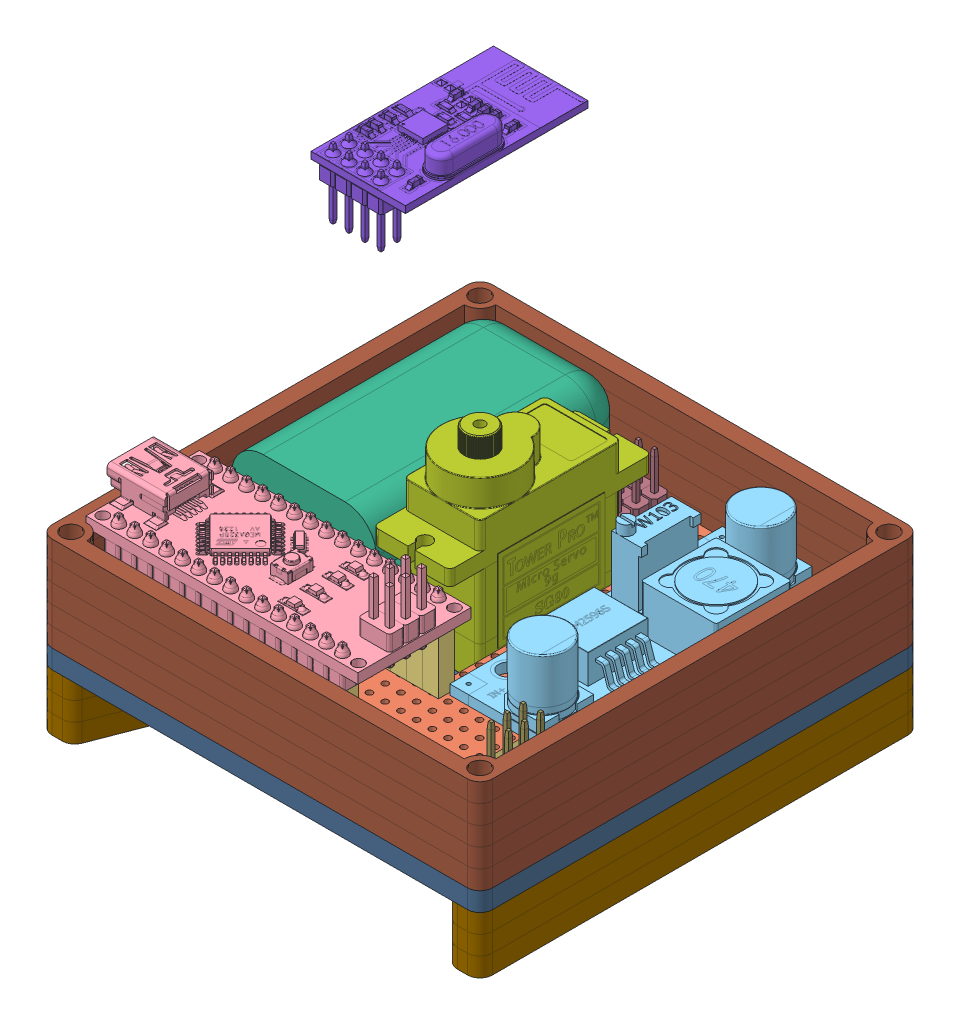
SolidWorks assembly base assembly modified, configuration Default. Lengths in mm.
Overall size (105.64 41.85 107.79).
27 component instances, 14 part files, 65 mates.
Components (placement in the parent):
- hex nut style 1_am-1: hex nut style 1_am [B18.2.4.1M - Hex nut, Style 1,  M3 x 0.5 --D-N] at (-15.0478 14.4 2.5048) x (1 0 0) z (0 1 0) size (5.5 6.35 2.4)
- hex nut style 1_am-2: hex nut style 1_am [B18.2.4.1M - Hex nut, Style 1,  M3 x 0.5 --D-N] at (-65.0478 12 2.5048) x (1 0 0) z (0 -1 0) size (5.5 6.35 2.4)
- hex nut style 1_am-3: hex nut style 1_am [B18.2.4.1M - Hex nut, Style 1,  M3 x 0.5 --D-N] at (-15.0478 14.4 52.5048) x (1 0 0) z (0 1 0) size (5.5 6.35 2.4)
- hex nut style 1_am-4: hex nut style 1_am [B18.2.4.1M - Hex nut, Style 1,  M3 x 0.5 --D-N] at (-65.0478 14.4 52.5048) x (1 0 0) z (0 1 0) size (5.5 6.35 2.4)
- pcb-2: pcb [Default] at (-72.9594 14.4 41.2771) x (0 0 1) z (-1 0 0) size (60 1 60)
- Arduino NanoV3 + Female Headers-1: Arduino NanoV3 + Female Headers [Default] at (-32.0594 27.95 40.8489) x (-1 0 0) z (0 0 1) size (38.1 11.45 17.78)
- arduino nano-1: arduino nano [Default] at (-36.1294 26.35 42.1189) x (-1 0 0) z (0 0 -1) size (45 18.6 18)
- LM2596 - small buck-1: LM2596 - small buck [Default] at (-14.3353 36.0469 -0.782) x (0 0 1) z (0 1 0) size (43.33 21.52 14.13)
- battery-1: battery [Default] at (-61.9173 22.4 17.6773) size (23 7 40)
- battery-2: battery [Default] at (-61.709 15.4 17.6773) size (23 7 40)
- SG90 - Micro Servo 9g - Tower Pro.1-1: SG90 - Micro Servo 9g - Tower Pro.1 [Peça] at (-42.9594 22.55 23.5273) x (0 0 -1) z (1 0 0) size (32.1 29.95 12.4)
- nRF24L01+_enhanced-1: nRF24L01+_enhanced [Default<As Machined>] at (-106.1029 21.6136 -29.6139) x (0 0 -1) z (1 0 0) size (29 12.85 15)
- stage-1: stage [Default] at (-42.9594 0 28.6773) size (70 3 70)
- base1-1: base1 [Default] at (-42.9594 12 28.6773) x (-1 0 0) z (0 0 1) size (70 3 70)
- stage-2: stage [Default] at (-42.9594 3 28.6773) size (70 3 70)
- stage-3: stage [Default] at (-42.9594 6 28.6773) size (70 3 70)
- walls-1: walls [Default] at (-42.9594 12 28.6773) size (70 3 70)
- walls-2: walls [Default] at (-42.9594 15 28.6773) size (70 3 70)
- walls-3: walls [Default] at (-42.9594 18 28.6773) size (70 3 70)
- walls-4: walls [Default] at (-42.9594 21 28.6773) size (70 3 70)
- walls-5: walls [Default] at (-42.9594 24 28.6773) size (70 3 70)
- Header, Male, 2.54mm, 1x3-1: Header, Male, 2.54mm, 1x3 [Default] at (-16.7434 15.146 45.2549) x (0 0 -1) z (1 0 0) size (7.62 11.54 2.54)
- Header, Male, 2.54mm, 1x3-2: Header, Male, 2.54mm, 1x3 [Default] at (-19.317 15.146 45.4589) x (0 0 -1) z (1 0 0) size (7.62 11.54 2.54)
- Header, Male, 2.54mm, 1x2-1: Header, Male, 2.54mm, 1x2 [Default] at (-44.122 15.146 5.6481) size (5.08 11.54 2.54)
- Header, Male, 2.54mm, 1x2-2: Header, Male, 2.54mm, 1x2 [Default] at (-44.0543 15.146 2.787) size (5.08 11.54 2.54)
- Header, Male, 2.54mm, 1x2-3: Header, Male, 2.54mm, 1x2 [Default] at (-43.947 15.146 -0.0213) size (5.08 11.54 2.54)
- base1nano-1: base1nano [Default] at (-42.9594 27 28.6773) x (0 0 1) z (-1 0 0) size (70 3 70) (hidden)
Mates (geometry in assembly coordinates):
- Coincident28: coincident anti-aligned: plane of stage-1 through (-41.814 0 3.6773) normal (0 -1 0); plane of assembly through (0 0 0) normal (0 1 0)
- Coincident29: coincident anti-aligned: plane of stage-1 through (-41.814 3 3.6773) normal (0 1 0); plane of stage-2 through (-41.814 3 3.6773) normal (0 -1 0)
- Coincident30: coincident aligned: plane of stage-1 through (-77.9594 3 -6.3227) normal (-1 0 0); plane of stage-2 through (-77.9594 6 -6.3227) normal (-1 0 0)
- Concentric11: concentric aligned: cylinder of stage-1 through (-75.4594 0 61.1773) axis (0 1 0) radius 1.4881; cylinder of stage-2 through (-75.4594 3 61.1773) axis (0 1 0) radius 1.4881
- Coincident31: coincident anti-aligned: plane of stage-2 through (-41.814 6 3.6773) normal (0 1 0); plane of stage-3 through (-41.814 6 3.6773) normal (0 -1 0)
- Coincident32: coincident aligned: plane of stage-1 through (-77.9594 3 -6.3227) normal (-1 0 0); plane of stage-3 through (-77.9594 9 -6.3227) normal (-1 0 0)
- Concentric12: concentric aligned: cylinder of stage-1 through (-75.4594 0 61.1773) axis (0 1 0) radius 1.4881; cylinder of stage-3 through (-75.4594 6 61.1773) axis (0 1 0) radius 1.4881
- Coincident35: coincident anti-aligned: plane of base1-1 through (-42.9594 9 28.6773) normal (0 -1 0); plane of stage-3 through (-41.814 9 3.6773) normal (0 1 0)
- Coincident36: coincident aligned: plane of base1-1 through (-77.9594 9 -6.3227) normal (-1 0 0); plane of stage-2 through (-77.9594 6 -6.3227) normal (-1 0 0)
- Concentric14: concentric aligned: cylinder of base1-1 through (-75.4594 9 61.1773) axis (0 1 0) radius 1.5; cylinder of stage-3 through (-75.4594 6 61.1773) axis (0 1 0) radius 1.4881
- Coincident37: coincident anti-aligned: plane of base1-1 through (-42.9594 12 28.6773) normal (0 1 0); plane of walls-1 through (-42.9594 12 28.6773) normal (0 -1 0)
- Coincident38: coincident aligned: plane of base1-1 through (-77.9594 9 -6.3227) normal (-1 0 0); plane of walls-1 through (-77.9594 15 -6.3227) normal (-1 0 0)
- Concentric15: concentric anti-aligned: cylinder of base1-1 through (-75.4594 9 61.1773) axis (0 1 0) radius 1.5; cylinder of walls-1 through (-75.4594 15 61.1773) axis (0 -1 0) radius 1.5
- Coincident39: coincident anti-aligned: plane of walls-1 through (-42.9594 15 28.6773) normal (0 1 0); plane of walls-2 through (-42.9594 15 28.6773) normal (0 -1 0)
- Coincident40: coincident aligned: plane of base1-1 through (-77.9594 9 -6.3227) normal (-1 0 0); plane of walls-2 through (-77.9594 18 -6.3227) normal (-1 0 0)
- Concentric16: concentric anti-aligned: cylinder of base1-1 through (-75.4594 9 61.1773) axis (0 1 0) radius 1.5; cylinder of walls-2 through (-75.4594 18 61.1773) axis (0 -1 0) radius 1.5
- Coincident41: coincident aligned: plane of base1-1 through (-77.9594 9 -6.3227) normal (-1 0 0); plane of walls-3 through (-77.9594 21 -6.3227) normal (-1 0 0)
- Concentric17: concentric anti-aligned: cylinder of base1-1 through (-75.4594 9 61.1773) axis (0 1 0) radius 1.5; cylinder of walls-3 through (-75.4594 21 61.1773) axis (0 -1 0) radius 1.5
- Coincident42: coincident anti-aligned: plane of walls-2 through (-42.9594 18 28.6773) normal (0 1 0); plane of walls-3 through (-42.9594 18 28.6773) normal (0 -1 0)
- Coincident43: coincident aligned: plane of base1-1 through (-77.9594 9 -6.3227) normal (-1 0 0); plane of walls-4 through (-77.9594 24 -6.3227) normal (-1 0 0)
- Concentric18: concentric anti-aligned: cylinder of base1-1 through (-75.4594 9 61.1773) axis (0 1 0) radius 1.5; cylinder of walls-4 through (-75.4594 24 61.1773) axis (0 -1 0) radius 1.5
- Coincident44: coincident anti-aligned: plane of walls-3 through (-42.9594 21 28.6773) normal (0 1 0); plane of walls-4 through (-42.9594 21 28.6773) normal (0 -1 0)
- Coincident45: coincident aligned: plane of base1-1 through (-77.9594 9 -6.3227) normal (-1 0 0); plane of walls-5 through (-77.9594 27 -6.3227) normal (-1 0 0)
- Concentric19: concentric anti-aligned: cylinder of base1-1 through (-75.4594 9 61.1773) axis (0 1 0) radius 1.5; cylinder of walls-5 through (-75.4594 27 61.1773) axis (0 -1 0) radius 1.5
- Coincident46: coincident anti-aligned: plane of walls-4 through (-42.9594 24 28.6773) normal (0 1 0); plane of walls-5 through (-42.9594 24 28.6773) normal (0 -1 0)
- Coincident49: coincident anti-aligned: plane of hex nut style 1_am-3 through (-20.5478 12 52.5048) normal (0 -1 0); plane of base1-1 through (-42.9594 12 28.6773) normal (0 1 0)
- Concentric21: concentric aligned: cylinder of hex nut style 1_am-3 through (-15.0478 12 52.5048) axis (0 1 0) radius 1.25; circle of assembly
- Coincident50: coincident anti-aligned: plane of hex nut style 1_am-1 through (-20.5478 12 2.5048) normal (0 -1 0); plane of base1-1 through (-42.9594 12 28.6773) normal (0 1 0)
- Concentric22: concentric aligned: cylinder of hex nut style 1_am-1 through (-15.0478 12 2.5048) axis (0 1 0) radius 1.25; circle of assembly
- Coincident51: coincident anti-aligned: plane of hex nut style 1_am-4 through (-70.5478 12 52.5048) normal (0 -1 0); plane of base1-1 through (-42.9594 12 28.6773) normal (0 1 0)
- Concentric23: concentric aligned: cylinder of hex nut style 1_am-4 through (-65.0478 12 52.5048) axis (0 1 0) radius 1.25; circle of assembly
- Coincident52: coincident anti-aligned: plane of hex nut style 1_am-2 through (-70.5478 12 2.5048) normal (0 -1 0); plane of base1-1 through (-42.9594 12 28.6773) normal (0 1 0)
- Concentric24: concentric anti-aligned: cylinder of hex nut style 1_am-2 through (-65.0478 14.4 2.5048) axis (0 -1 0) radius 1.25; circle of assembly
- Coincident53: coincident anti-aligned: plane of hex nut style 1_am-4 through (-70.5478 14.4 52.5048) normal (0 1 0); plane of pcb-2 through (-72.9594 14.4 41.2771) normal (0 -1 0)
- Concentric25: concentric anti-aligned: cylinder of SG90 - Micro Servo 9g - Tower Pro.1-1 through (-42.9594 38.75 28.6773) axis (0 -1 0) radius 6.1; circle of assembly
- Parallel8: parallel aligned: plane of SG90 - Micro Servo 9g - Tower Pro.1-1 through (-48.2094 12 12.2773) normal (0 0 -1); plane of walls-5 through (-77.9594 27 -6.3227) normal (0 0 -1)
- Coincident55: coincident anti-aligned: plane of SG90 - Micro Servo 9g - Tower Pro.1-1 through (-37.7094 12 33.9273) normal (0 -1 0); circle of assembly
- Parallel10: parallel: plane of SG90 - Micro Servo 9g - Tower Pro.1-1 through (-49.0594 30.2 38.7273) normal (-1 0 0); line of assembly
- Coincident58: coincident anti-aligned: plane of pcb-2 through (-49.0594 15.4 39.8789) normal (1 0 0); plane of SG90 - Micro Servo 9g - Tower Pro.1-1 through (-49.0594 30.2 38.7273) normal (-1 0 0)
- Lock2: lock: unknown of pcb-2; unknown of walls-5
- Coincident60: coincident anti-aligned: plane of pcb-2 through (-72.9594 15.4 41.2771) normal (0 1 0); plane of battery-2 through (-61.709 15.4 17.6773) normal (0 -1 0)
- Coincident64: coincident aligned: plane of battery-1 through (-73.4173 29.4 37.6773) normal (0 0 1); plane of battery-2 through (-73.209 22.4 37.6773) normal (0 0 1)
- Coincident65: coincident anti-aligned: plane of battery-1 through (-61.9173 22.4 17.6773) normal (0 -1 0); plane of battery-2 through (-61.709 22.4 17.6773) normal (0 1 0)
- Distance2: distance = 26 mm aligned: plane of battery-2 through (-73.209 22.4 37.6773) normal (0 0 1); plane of walls-4 through (-77.9594 24 63.6773) normal (0 0 1)
- Coincident72: coincident anti-aligned: plane of pcb-2 through (-72.9594 15.4 41.2771) normal (0 1 0); plane of Arduino NanoV3 + Female Headers-1 through (-58.9894 15.4 42.1189) normal (0 -1 0)
- Coincident73: coincident: line of pcb-2 through (-72.9594 15.4 58.6289) axis (1 0 0); plane of Arduino NanoV3 + Female Headers-1 through (-39.9394 15.4 58.6289) normal (0 0 1)
- Coincident74: coincident: line of pcb-2 through (-72.9594 15.4 -1.3711) axis (0 0 1); plane of Arduino NanoV3 + Female Headers-1 through (-72.9594 15.4 56.0889) normal (-1 0 0)
- Coincident75: coincident anti-aligned: plane of Arduino NanoV3 + Female Headers-1 through (-53.9094 23.85 57.3589) normal (0 1 0); plane of arduino nano-1 through (-36.8994 23.85 56.5889) normal (0 -1 0)
- Coincident76: coincident aligned: plane of Arduino NanoV3 + Female Headers-1 through (-50.0994 15.4 58.6289) normal (0 0 1); plane of arduino nano-1 through (-47.0594 23.85 58.6289) normal (0 0 1)
- Coincident77: coincident aligned: plane of Arduino NanoV3 + Female Headers-1 through (-34.8594 15.4 58.6289) normal (1 0 0); plane of arduino nano-1 through (-34.8594 23.85 58.1289) normal (1 0 0)
- Lock3: lock: unknown of base1-1
- Parallel16: parallel aligned: plane of walls-2 through (-77.9594 18 -6.3227) normal (0 0 -1); plane of Header, Male, 2.54mm, 1x2-1 through (-45.392 17.686 4.3781) normal (0 0 -1)
- Coincident86: coincident anti-aligned: plane of pcb-2 through (-72.9594 15.4 41.2771) normal (0 1 0); plane of Header, Male, 2.54mm, 1x2-1 through (-46.662 15.4 5.6481) normal (0 -1 0)
- Parallel18: parallel aligned: plane of walls-2 through (-77.9594 18 -6.3227) normal (0 0 -1); plane of Header, Male, 2.54mm, 1x2-2 through (-45.3243 17.686 1.517) normal (0 0 -1)
- Coincident87: coincident anti-aligned: plane of pcb-2 through (-72.9594 15.4 41.2771) normal (0 1 0); plane of Header, Male, 2.54mm, 1x2-2 through (-46.5943 15.4 2.787) normal (0 -1 0)
- Parallel19: parallel aligned: plane of walls-2 through (-77.9594 18 -6.3227) normal (0 0 -1); plane of Header, Male, 2.54mm, 1x2-3 through (-45.217 17.686 -1.2913) normal (0 0 -1)
- Coincident88: coincident anti-aligned: plane of pcb-2 through (-72.9594 15.4 41.2771) normal (0 1 0); plane of Header, Male, 2.54mm, 1x2-3 through (-46.487 15.4 -0.0213) normal (0 -1 0)
- Concentric26: concentric aligned: cylinder of walls-5 through (-10.4594 27 -3.8227) axis (0 -1 0) radius 1.5; cylinder of base1nano-1 through (-10.4594 30 -3.8227) axis (0 -1 0) radius 1.5
- Coincident90: coincident anti-aligned: plane of walls-5 through (-42.9594 27 28.6773) normal (0 1 0); plane of base1nano-1 through (-42.9594 27 28.6773) normal (0 -1 0)
- Coincident91: coincident aligned: plane of walls-4 through (-77.9594 24 -6.3227) normal (0 0 -1); plane of base1nano-1 through (-7.9594 30 -6.3227) normal (0 0 -1)
- Coincident94: coincident anti-aligned: plane of pcb-2 through (-72.9594 15.4 41.2771) normal (0 1 0); plane of LM2596 - small buck-1 through (-23.5 15.4 20.245) normal (0 -1 0)
- Coincident96: coincident anti-aligned: line of pcb-2 through (-12.9594 15.4 58.6289) axis (0 0 -1); line of LM2596 - small buck-1 through (-12.9594 15.4 1.6289) axis (0 0 1)
- Coincident99: coincident: line of pcb-2 through (-12.9594 15.4 -1.3711) axis (-1 0 0); plane of LM2596 - small buck-1 through (-30.3714 16.9539 -1.3711) normal (0 0 -1)
- Coincident100: coincident anti-aligned: plane of pcb-2 through (-72.9594 15.4 41.2771) normal (0 1 0); plane of Header, Male, 2.54mm, 1x3-1 through (-16.7434 15.4 50.3349) normal (0 -1 0)
- Coincident102: coincident anti-aligned: plane of pcb-2 through (-72.9594 15.4 41.2771) normal (0 1 0); plane of Header, Male, 2.54mm, 1x3-2 through (-19.317 15.4 50.5389) normal (0 -1 0)
